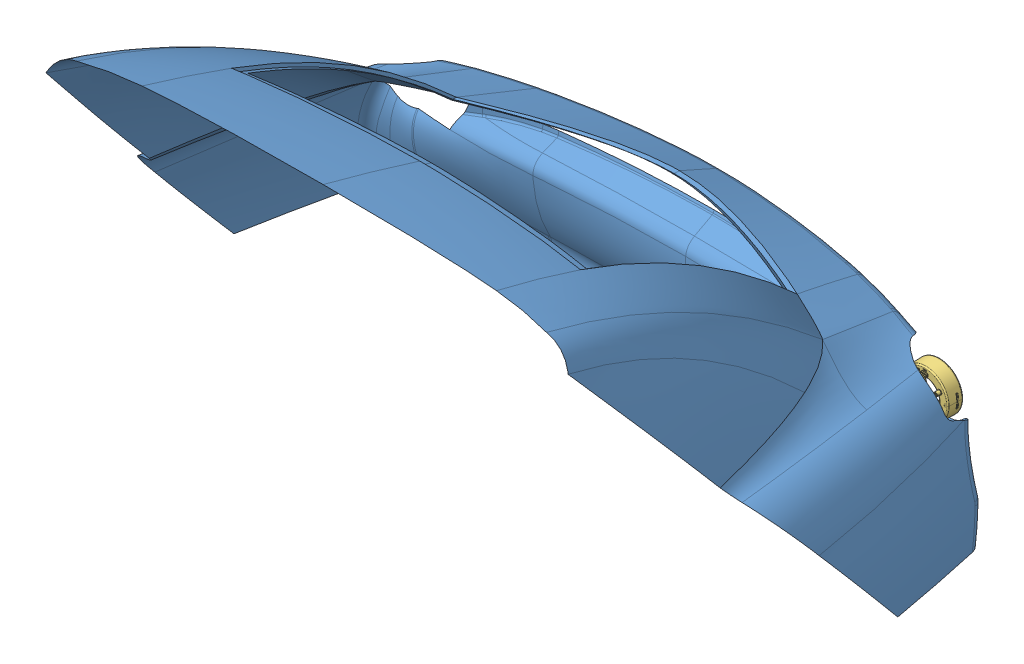
SolidWorks assembly 0204100-1-00 KLAPA_BAG, configuration Domyślna. Lengths in mm.
Overall size (1653.23 801.68 1361.49).
3 component instances, 3 part files, 2 mates.
Components (placement in the parent):
- 0204100-1-01 LAMINAT-KLAPA-BAG-1: 0204100-1-01 LAMINAT-KLAPA-BAG [Domyślna] at origin size (1653.23 801.68 1361.49)
- HELLA_3D_data_LED_rear_lamp_Strip_Lamp_2BA-980-88-1: HELLA_3D_data_LED_rear_lamp_Strip_Lamp_2BA-980-88 [Domyślna] at (376.6153 682.0031 -3410) x (-1 0 0) z (0 0 -1) size (288.32 25.1 16.53)
- HELLA_3D_data_LED_rear_lamp_ring_module_112_mm_2SB-009-36.stp-1: HELLA_3D_data_LED_rear_lamp_ring_module_112_mm_2SB-009-36.stp [Domyślna] at (628.2676 654.8723 -3352.1669) size (123.49 118.94 241.71)
Mates (geometry in assembly coordinates):
- Odległość1: distance = 3410 mm: plane of assembly through (0 0 0) normal (0 0 1); plane of assembly; plane of HELLA_3D_data_LED_rear_lamp_Strip_Lamp_2BA-980-88-1 through (376.6153 682.0031 -3410) normal (0 0 -1)
- Równolegle1: parallel aligned: plane of HELLA_3D_data_LED_rear_lamp_Strip_Lamp_2BA-980-88-1 through (376.6153 682.0031 -3410) normal (0 1 0)
